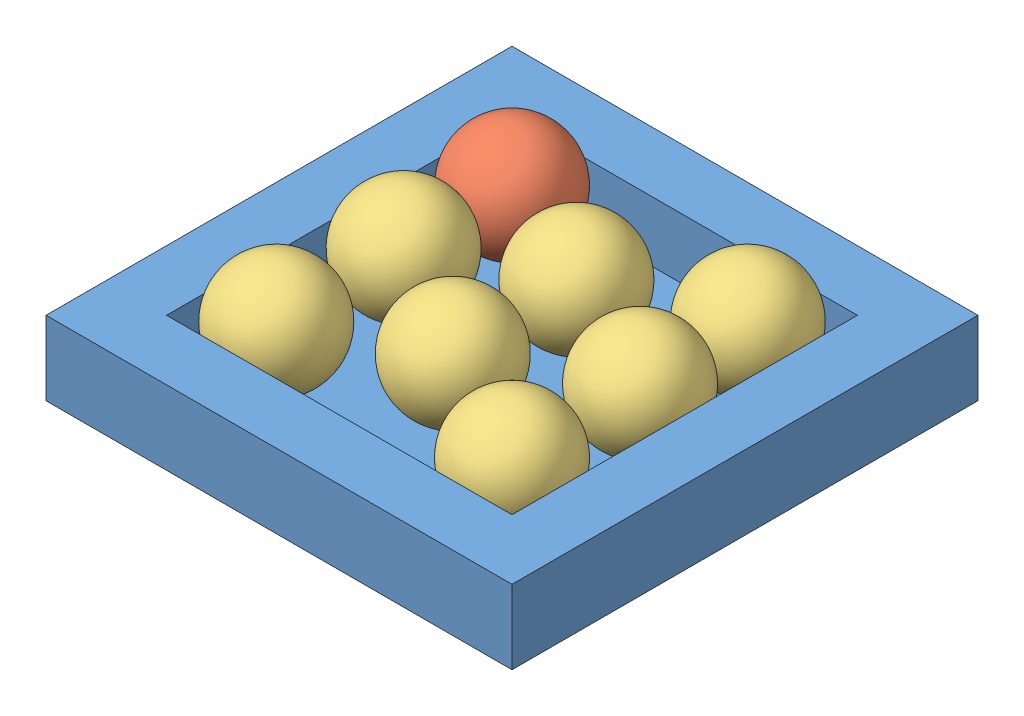
SolidWorks assembly Plateau_Cerises_bleues, configuration Défaut. Lengths in mm.
Overall size (170 62.52 170).
9 component instances, 3 part files, 18 mates.
Components (placement in the parent):
- Plateau-1: Plateau [Défaut] at (-100.5612 -27.0402 0) size (170 27 170)
- Cerise_bleue_2-1: Cerise_bleue_2 [Défaut] at (-58.5612 -22.0402 -128) size (40 40 40)
- Cerise_blanche_2-9: Cerise_blanche_2 [Défaut] at (-17.0336 -22.0402 -109.9731) size (40 40 40)
- Cerise_blanche_2-12: Cerise_blanche_2 [Défaut] at (27.4388 -22.0402 -42) size (40 40 40)
- Cerise_blanche_2-8: Cerise_blanche_2 [Défaut] at (-16.2105 -22.0402 -64.051) size (40 40 40)
- Cerise_blanche_2-10: Cerise_blanche_2 [Défaut] at (26.5177 -20.5303 -96.2764) x (0.998898 -0.046056 -0.009055) z (-0.009055 -0.378387 0.925603) size (40 40 40)
- Cerise_blanche_2-7: Cerise_blanche_2 [Défaut] at (-69.0812 -14.2205 -30.1268) x (0.803023 -0.125716 0.582537) z (-0.28014 0.783135 0.555176) size (40 40 40)
- Cerise_blanche_2-6: Cerise_blanche_2 [Défaut] at (-66.6772 -18.9858 -95.3197) x (0.870305 -0.243717 -0.427985) z (0.279098 -0.471938 0.836289) size (40 40 40)
- Cerise_blanche_2-11: Cerise_blanche_2 [Défaut] at (35.7969 -19.5803 -132.7423) x (0.886091 0.335873 0.319424) z (-0.200496 -0.343593 0.917467) size (40 40 40)
Mates (geometry in assembly coordinates):
- Tangent1: tangent anti-aligned: plane of Plateau-1 through (-100.5612 -22.0402 -170) normal (0 1 0); sphere of Cerise_bleue_2-1
- Tangent2: tangent anti-aligned: plane of Plateau-1 through (-100.5612 -22.0402 -170) normal (0 1 0); sphere of Cerise_blanche_2-9
- Tangent3: tangent anti-aligned: plane of Plateau-1 through (-100.5612 -22.0402 -170) normal (0 1 0); sphere of Cerise_blanche_2-11
- Tangent4: tangent anti-aligned: plane of Plateau-1 through (-100.5612 -22.0402 -170) normal (0 1 0); sphere of Cerise_blanche_2-10
- Tangent5: tangent anti-aligned: plane of Plateau-1 through (-100.5612 -22.0402 -170) normal (0 1 0); sphere of Cerise_blanche_2-8
- Tangent6: tangent anti-aligned: plane of Plateau-1 through (-100.5612 -22.0402 -170) normal (0 1 0); sphere of Cerise_blanche_2-12
- Tangent7: tangent anti-aligned: plane of Plateau-1 through (-100.5612 -22.0402 -170) normal (0 1 0); sphere of Cerise_blanche_2-7
- Tangent8: tangent anti-aligned: plane of Plateau-1 through (-100.5612 -22.0402 -170) normal (0 1 0); sphere of Cerise_blanche_2-6
- Tangent9: tangent anti-aligned: plane of Plateau-1 through (-78.5612 -0.0402 -148) normal (0 0 1); sphere of Cerise_bleue_2-1
- Tangent11: tangent anti-aligned: plane of Plateau-1 through (-78.5612 -0.0402 -148) normal (1 0 0); sphere of Cerise_bleue_2-1
- Tangent12: tangent anti-aligned: plane of Plateau-1 through (-78.5612 -0.0402 -148) normal (0 0 1); sphere of Cerise_blanche_2-11
- Tangent13: tangent anti-aligned: plane of Plateau-1 through (47.4388 -0.0402 -148) normal (-1 0 0); sphere of Cerise_blanche_2-11
- Tangent14: tangent anti-aligned: plane of Plateau-1 through (-78.5612 -0.0402 -148) normal (1 0 0); sphere of Cerise_blanche_2-6
- Tangent15: tangent anti-aligned: plane of Plateau-1 through (-78.5612 -0.0402 -148) normal (1 0 0); sphere of Cerise_blanche_2-7
- Tangent16: tangent anti-aligned: plane of Plateau-1 through (-78.5612 -0.0402 -22) normal (0 0 -1); sphere of Cerise_blanche_2-7
- Tangent17: tangent anti-aligned: plane of Plateau-1 through (-78.5612 -0.0402 -22) normal (0 0 -1); sphere of Cerise_blanche_2-12
- Tangent18: tangent anti-aligned: plane of Plateau-1 through (47.4388 -0.0402 -148) normal (-1 0 0); sphere of Cerise_blanche_2-12
- Tangent19: tangent anti-aligned: plane of Plateau-1 through (47.4388 -0.0402 -148) normal (-1 0 0); sphere of Cerise_blanche_2-10
